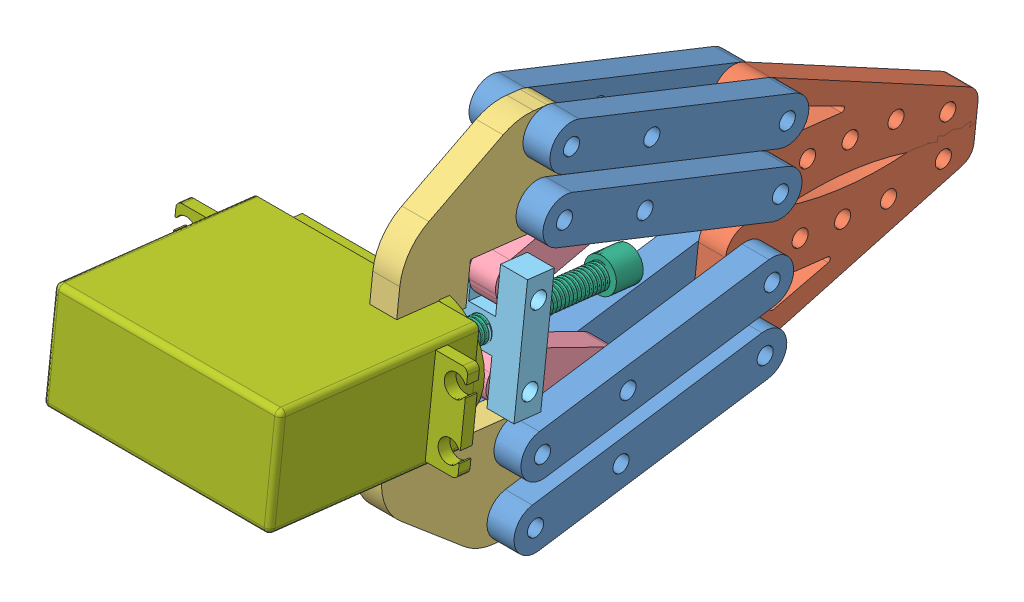
SolidWorks assembly UP1 GRIPPER, configuration Default. Lengths in mm.
Overall size (54 99.81 140.97).
17 component instances, 7 part files, 30 mates.
Components (placement in the parent):
- UP1-1: UP1 [Default] at (37.8309 -63.6464 28.527) x (1 0 0) z (0 -0.773827 0.633397) size (5 36.9 39.84)
- UP1-2: UP1 [Default] at (27.8309 -74.7762 29.7197) x (1 0 0) z (0 -0.774506 0.632566) size (5 36.9 39.84)
- UP1-3: UP1 [Default] at (42.8309 132.7011 5.9434) x (-1 0 0) z (0 0.897422 0.441173) size (5 36.9 39.84)
- UP1-4: UP1 [Default] at (32.8309 132.7011 5.9434) x (-1 0 0) z (0 0.897422 0.441173) size (5 36.9 39.84)
- UP1-5: UP1 [Default] at (27.8309 -63.6464 28.527) x (1 0 0) z (0 -0.773827 0.633397) size (5 36.9 39.84)
- UP1-6: UP1 [Default] at (37.8309 -74.7762 29.7197) x (1 0 0) z (0 -0.774506 0.632566) size (5 36.9 39.84)
- UP1-7: UP1 [Default] at (42.8309 143.811 4.5781) x (-1 0 0) z (0 0.897895 0.440209) size (5 36.9 39.84)
- UP1-8: UP1 [Default] at (32.8309 143.811 4.5781) x (-1 0 0) z (0 0.897895 0.440209) size (5 36.9 39.84)
- UP2-1: UP2 [Default] at (37.8309 80.9278 78.3806) x (0 -0.113199 -0.993572) z (-1 0 0) size (46.25 22.4 5)
- UP2-2: UP2 [Default] at (32.8309 3.2205 87.3184) x (0 -0.115332 -0.993327) z (1 0 0) size (46.25 22.4 5)
- UP3-1: UP3 [Default] at (32.8309 -56.8999 124.1735) x (1 0 0) z (0 0.114265 0.99345) size (5 26.6 29.3)
- UP3-2: UP3 [Default] at (37.8309 147.8457 100.6239) x (-1 0 0) z (0 0.114265 0.99345) size (5 26.6 29.3)
- UP4-1: UP4 [Default] at (32.8309 -26.3147 34.5726) x (1 0 0) z (0 -0.898573 0.438823) size (5 27.07 8)
- UP4-2: UP4 [Default] at (32.8309 3.8249 -1.2083) x (1 0 0) z (0 -0.974737 -0.223358) size (5 27.07 8)
- UP5-1: UP5 [Default] at (-106.5791 -176.9863 61.7493) x (0 0.114265 0.99345) z (0 0.99345 -0.114265) size (5.26 15 22)
- UP6-1: UP6 [Default] at (35.3309 34.8363 19.9214) x (0.989877 0.140999 -0.016217) z (0 0.114265 0.99345) size (6 6 45)
- SERVO motor - Copy-1: SERVO motor - Copy [Default] at (34.3525 31.7522 76.2474) x (1 0 0) z (0 0.114265 0.99345) size (54 20 40.7)
Mates (geometry in assembly coordinates):
- Coincident1: coincident: circle of UP4-2; circle of UP5-1
- Coincident3: coincident: circle of UP4-1; circle of UP5-1
- Coincident4: coincident: circle of UP1-8; circle of UP3-2
- Coincident5: coincident: circle of UP1-7; circle of UP3-2
- Coincident6: coincident: circle of UP1-4; circle of UP3-2
- Coincident7: coincident: circle of UP1-3; circle of UP3-2
- Coincident8: coincident: circle of UP1-4; circle of UP4-2
- Coincident9: coincident: circle of UP1-3; circle of UP4-2
- Coincident10: coincident: circle of UP1-8; circle of UP2-1
- Coincident11: coincident: circle of UP1-4; circle of UP2-1
- Concentric3: concentric: cylinder of UP1-7 through (37.8309 49.7438 -7.237) axis (1 0 0) radius 1.5; cylinder of UP2-1 through (32.8309 49.7438 -7.237) axis (1 0 0) radius 1.5
- Coincident15: coincident: circle of UP1-5; cylinder of UP3-1 through (37.8309 18.9195 38.1005) axis (-1 0 0) radius 1.5
- Coincident16: coincident: circle of UP1-1; circle of UP3-1
- Coincident17: coincident: circle of UP1-2; circle of UP3-1
- Coincident18: coincident: cylinder of UP1-6 through (42.8309 7.7794 39.3818) axis (-1 0 0) radius 1.5; circle of UP3-1
- Concentric4: concentric: cylinder of UP6-1 through (35.3309 39.4069 59.6594) axis (0 -0.114265 -0.99345) radius 1.5; cylinder of SERVO motor - Copy-1 through (35.3309 39.4069 59.6594) axis (0 -0.114265 -0.99345) radius 1.55
- Coincident20: coincident: plane of UP3-2 through (32.8309 140.8313 39.639) normal (0 0.114265 0.99345); plane of SERVO motor - Copy-1 through (35.3309 38.4585 51.4138) normal (0 -0.114265 -0.99345)
- Coincident21: coincident: plane of UP3-2 through (32.8309 54.9107 111.3132) normal (0 -0.99345 0.114265); plane of SERVO motor - Copy-1 through (34.3525 50.6277 74.0764) normal (0 0.99345 -0.114265)
- Coincident22: coincident: plane of UP3-1 through (37.8309 36.0351 113.4842) normal (0 0.99345 -0.114265); plane of SERVO motor - Copy-1 through (34.3525 31.7522 76.2474) normal (0 -0.99345 0.114265)
- Coincident23: coincident: plane of UP3-1 through (37.8309 -63.9143 63.1885) normal (0 0.114265 0.99345); plane of SERVO motor - Copy-1 through (35.3309 38.4585 51.4138) normal (0 -0.114265 -0.99345)
- Concentric5: concentric: cylinder of UP1-5 through (32.8309 21.2749 22.2672) axis (-1 0 0) radius 1.5; cylinder of UP4-1 through (37.8309 21.2749 22.2672) axis (-1 0 0) radius 1.5
- Coincident26: coincident: circle of UP1-5; circle of UP3-1
- Coincident27: coincident: circle of UP1-1; circle of UP4-1
- Coincident28: coincident: circle of UP1-6; circle of UP3-1
- Coincident29: coincident: circle of UP1-1; circle of UP2-2
- Coincident30: coincident: circle of UP1-2; circle of UP2-2
- Coincident31: coincident: circle of UP1-6; circle of UP2-2
- Coincident33: coincident: plane of UP6-1 through (35.3309 39.4069 59.6594) normal (0 0.114265 0.99345); plane of SERVO motor - Copy-1 through (35.3309 39.4069 59.6594) normal (0 -0.114265 -0.99345)
- LimitDistance1: limit distance = 7.65 mm: plane of UP5-1 through (-106.5791 -176.415 66.7166) normal (0 0.114265 0.99345); plane of SERVO motor - Copy-1 through (35.3309 38.2642 49.7249) normal (0 -0.114265 -0.99345)
- Screw1: screw = 0.75 mm: cylinder of UP5-1 through (35.3309 36.2474 32.1905) axis (0 0.114265 0.99345) radius 2.1875; cylinder of UP6-1 through (35.3309 34.2649 14.9542) axis (0 0.114265 0.99345) radius 3
